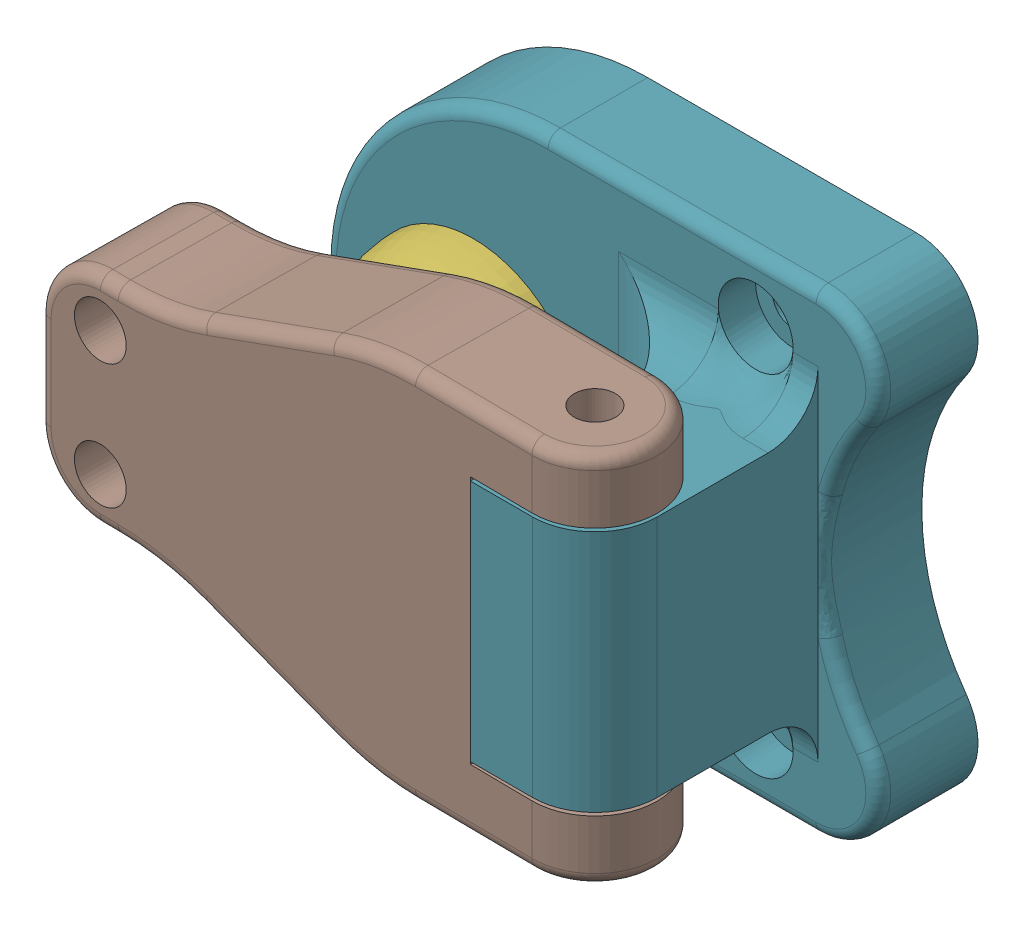
SolidWorks assembly Shifter, configuration Default. Lengths in mm.
Overall size (49.89 38 31.54).
2 component instances, 2 part files, 2 mates.
Components (placement in the parent):
- ShiftAdapter-1: ShiftAdapter [Default] at (601.1599 895.0487 1292.1507) size (44.51 38 31.49)
- Lever-1: Lever [Default] at (576.8245 895.0487 1313.0507) x (0.999945 0 0.010513) z (0 -1 0) size (45 10 30)
Mates (geometry in assembly coordinates):
- Concentric2: concentric anti-aligned: circle of ShiftAdapter-1; cylinder of Lever-1 through (576.8245 880.0487 1313.0507) axis (0 1 0) radius 1.65
- Distance1: distance = 0.25 mm anti-aligned: plane of Lever-1 through (576.8245 905.0487 1313.0507) normal (0 -1 0); plane of ShiftAdapter-1 through (576.8245 904.7987 1313.0507) normal (0 1 0)
